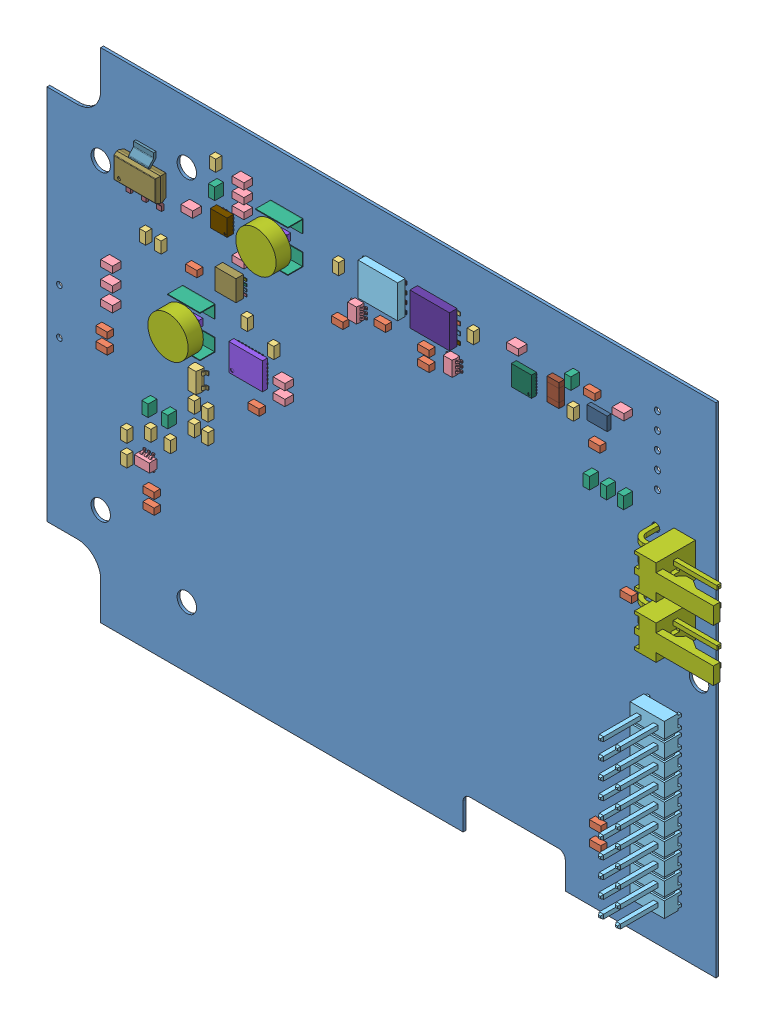
SolidWorks assembly PowerBoard, configuration Domyślna. Lengths in mm.
Overall size (104.97 74.1 12.18).
255 component instances, 64 part files, 0 mates.
Components (placement in the parent):
- PowerBoard.step-1: PowerBoard.step [Domyślna] at origin size (104.97 74.1 12.18)
  - Board.step-1: Board.step [Domyślna] at origin size (99.5 74.1 0.41)
    - Open CASCADE STEP translator 6.8 2.1.1.step-1: Open CASCADE STEP translator 6.8 2.1.1.step [Domyślna] at (0 0 -0.4115) size (99.5 74.1 0.41)
  - R13.step-1: R13.step [Domyślna] at origin size (1.7 0.95 0.9)
    - 6265950816.step-1: 6265950816.step [Domyślna] at (107.823 36.83 0) size (1.7 0.95 0.9)
      - Extruded.step-1: Extruded.step [Domyślna] at origin size (1.7 0.95 0.9)
  - R12.step-1: R12.step [Domyślna] at origin size (1.7 0.95 0.9)
    - 6265950816.step-1: 6265950816.step [Domyślna] at (107.823 34.29 0) size (1.7 0.95 0.9)
      - Extruded.step-1: Extruded.step [Domyślna] at origin size (1.7 0.95 0.9)
  - R41.step-1: R41.step [Domyślna] at origin size (0.95 1.7 0.9)
    - 6265951296.step-1: 6265951296.step [Domyślna] at (44.196 54.102 0) size (0.95 1.7 0.9)
      - Extruded-0.step-1: Extruded-0.step [Domyślna] at origin size (0.95 1.7 0.9)
  - T1.step-1: T1.step [Domyślna] at origin size (2.2 2.4 1.1)
    - SOT65P210X110-6N.step-1: SOT65P210X110-6N.step [Domyślna] at (40.6399 50.0381 0) x (0 1 0) z (0 0 1) size (2.4 2.2 1.1)
  - R22.step-1: R22.step [Domyślna] at origin size (0.95 1.7 0.9)
    - 6265951296.step-1: 6265951296.step [Domyślna] at (41.275 54.102 0) size (0.95 1.7 0.9)
      - Extruded-0.step-1: Extruded-0.step [Domyślna] at origin size (0.95 1.7 0.9)
  - R21.step-1: R21.step [Domyślna] at origin size (0.95 1.7 0.9)
    - 6265951296.step-1: 6265951296.step [Domyślna] at (37.719 49.022 0) size (0.95 1.7 0.9)
      - Extruded-0.step-1: Extruded-0.step [Domyślna] at origin size (0.95 1.7 0.9)
  - R20.step-1: R20.step [Domyślna] at origin size (1.7 0.95 0.9)
    - 6265950816.step-1: 6265950816.step [Domyślna] at (41.402 44.577 0) size (1.7 0.95 0.9)
      - Extruded.step-1: Extruded.step [Domyślna] at origin size (1.7 0.95 0.9)
  - R19.step-1: R19.step [Domyślna] at origin size (1.7 0.95 0.9)
    - 6265950816.step-1: 6265950816.step [Domyślna] at (41.402 46.609 0) size (1.7 0.95 0.9)
      - Extruded.step-1: Extruded.step [Domyślna] at origin size (1.7 0.95 0.9)
  - R18.step-1: R18.step [Domyślna] at origin size (0.95 1.7 0.9)
    - 6265951296.step-1: 6265951296.step [Domyślna] at (37.719 52.197 0) size (0.95 1.7 0.9)
      - Extruded-0.step-1: Extruded-0.step [Domyślna] at origin size (0.95 1.7 0.9)
  - R11.step-1: R11.step [Domyślna] at origin size (1.7 0.95 0.9)
    - 6265950816.step-1: 6265950816.step [Domyślna] at (112.395 68.707 0) size (1.7 0.95 0.9)
      - Extruded.step-1: Extruded.step [Domyślna] at origin size (1.7 0.95 0.9)
  - P1.step-1: P1.step [Domyślna] at origin size (5.08 25.4 11.3)
    - SAMTEC_TSW-110-23-L-D.step-1: SAMTEC_TSW-110-23-L-D.step [Domyślna] at (117.2211 44.4499 0) x (0 -1 0) z (0 0 1) size (25.4 5.08 11.3)
  - C16.step-1: C16.step [Domyślna] at origin size (0.95 1.75 1.3)
    - 6265949696.step-1: 6265949696.step [Domyślna] at (44.196 57.531 0) size (0.95 1.75 1.3)
      - Extruded-1.step-1: Extruded-1.step [Domyślna] at origin size (0.95 1.75 1.3)
  - C15.step-1: C15.step [Domyślna] at origin size (0.95 1.75 1.3)
    - 6265949696.step-1: 6265949696.step [Domyślna] at (41.275 57.531 0) size (0.95 1.75 1.3)
      - Extruded-1.step-1: Extruded-1.step [Domyślna] at origin size (0.95 1.75 1.3)
  - RTC.step-1: RTC.step [Domyślna] at origin size (14.74 5.08 9.64)
    - MOLEX_22-05-7028.step-1: MOLEX_22-05-7028.step [Domyślna] at (115.9486 69.977 0) x (0 -1 0) z (0 0 1) size (5.08 14.74 9.64)
  - EXT.step-1: EXT.step [Domyślna] at origin size (14.74 5.08 9.64)
    - MOLEX_22-05-7028.step-1: MOLEX_22-05-7028.step [Domyślna] at (115.9511 77.724 0) x (0 -1 0) z (0 0 1) size (5.08 14.74 9.64)
  - C3.step-1: C3.step [Domyślna] at origin size (0.95 1.75 1.3)
    - 6265949696.step-1: 6265949696.step [Domyślna] at (112.014 81.026 0) size (0.95 1.75 1.3)
      - Extruded-1.step-1: Extruded-1.step [Domyślna] at origin size (0.95 1.75 1.3)
  - C2.step-1: C2.step [Domyślna] at origin size (0.95 1.75 1.3)
    - 6265949696.step-1: 6265949696.step [Domyślna] at (109.474 81.026 0) size (0.95 1.75 1.3)
      - Extruded-1.step-1: Extruded-1.step [Domyślna] at origin size (0.95 1.75 1.3)
  - C1.step-1: C1.step [Domyślna] at origin size (0.95 1.75 1.3)
    - 6265949696.step-1: 6265949696.step [Domyślna] at (106.934 81.026 0) size (0.95 1.75 1.3)
      - Extruded-1.step-1: Extruded-1.step [Domyślna] at origin size (0.95 1.75 1.3)
  - IC3.step-1: IC3.step [Domyślna] at origin size (1.45 1.1 0.6)
    - 5965230816.step-1: 5965230816.step [Domyślna] at (34.417 59.055 -0.4115) x (0 -1 0) z (0 0 -1) size (1.1 1.45 0.6)
      - Body.step-1: Body.step [Domyślna] at origin size (1 1.45 0.55)
      - PinsArrayLR.step-1: PinsArrayLR.step [Domyślna] at origin size (1.1 1.2 0.07)
  - U1.step-1: U1.step [Domyślna] at origin size (3 2 0.6)
    - 6265946736.step-1: 6265946736.step [Domyślna] at (107.823 89.281 0) size (3 2 0.6)
      - Extruded-2.step-1: Extruded-2.step [Domyślna] at origin size (3 2 0.6)
  - R34.step-1: R34.step [Domyślna] at origin size (0.95 1.7 0.9)
    - 6265951296.step-1: 6265951296.step [Domyślna] at (59.563 73.914 0) size (0.95 1.7 0.9)
      - Extruded-0.step-1: Extruded-0.step [Domyślna] at origin size (0.95 1.7 0.9)
  - R33.step-1: R33.step [Domyślna] at origin size (0.95 1.7 0.9)
    - 6265951296.step-1: 6265951296.step [Domyślna] at (42.799 79.121 0) size (0.95 1.7 0.9)
      - Extruded-0.step-1: Extruded-0.step [Domyślna] at origin size (0.95 1.7 0.9)
  - R32.step-1: R32.step [Domyślna] at origin size (1.7 0.95 0.9)
    - 6265950816.step-1: 6265950816.step [Domyślna] at (75.819 85.344 0) size (1.7 0.95 0.9)
      - Extruded.step-1: Extruded.step [Domyślna] at origin size (1.7 0.95 0.9)
  - R31.step-1: R31.step [Domyślna] at origin size (0.95 1.7 0.9)
    - 6265951296.step-1: 6265951296.step [Domyślna] at (40.513 79.121 0) size (0.95 1.7 0.9)
      - Extruded-0.step-1: Extruded-0.step [Domyślna] at origin size (0.95 1.7 0.9)
  - R30.step-1: R30.step [Domyślna] at origin size (0.95 1.7 0.9)
    - 6265951296.step-1: 6265951296.step [Domyślna] at (69.215 89.535 0) size (0.95 1.7 0.9)
      - Extruded-0.step-1: Extruded-0.step [Domyślna] at origin size (0.95 1.7 0.9)
  - R29.step-1: R29.step [Domyślna] at origin size (1.7 0.95 0.9)
    - 6265950816.step-1: 6265950816.step [Domyślna] at (47.752 78.359 0) size (1.7 0.95 0.9)
      - Extruded.step-1: Extruded.step [Domyślna] at origin size (1.7 0.95 0.9)
  - R28.step-1: R28.step [Domyślna] at origin size (1.7 0.95 0.9)
    - 6265950816.step-1: 6265950816.step [Domyślna] at (107.696 85.725 0) size (1.7 0.95 0.9)
      - Extruded.step-1: Extruded.step [Domyślna] at origin size (1.7 0.95 0.9)
  - R27.step-1: R27.step [Domyślna] at origin size (1.75 3.35 0.8)
    - RESC3216X80N.step-1: RESC3216X80N.step [Domyślna] at (101.4729 89.5351 0) x (0 1 0) z (0 0 1) size (3.35 1.75 0.8)
  - R26.step-1: R26.step [Domyślna] at origin size (1.7 0.95 0.9)
    - 6265950816.step-1: 6265950816.step [Domyślna] at (69.469 82.55 0) size (1.7 0.95 0.9)
      - Extruded.step-1: Extruded.step [Domyślna] at origin size (1.7 0.95 0.9)
  - R25.step-1: R25.step [Domyślna] at origin size (1.7 0.95 0.9)
    - 6265950816.step-1: 6265950816.step [Domyślna] at (82.296 83.4136 0) size (1.7 0.95 0.9)
      - Extruded.step-1: Extruded.step [Domyślna] at origin size (1.7 0.95 0.9)
  - R24.step-1: R24.step [Domyślna] at origin size (0.95 1.7 0.9)
    - 6265951296.step-1: 6265951296.step [Domyślna] at (104.14 88.265 0) size (0.95 1.7 0.9)
      - Extruded-0.step-1: Extruded-0.step [Domyślna] at origin size (0.95 1.7 0.9)
  - R23.step-1: R23.step [Domyślna] at origin size (1.7 0.95 0.9)
    - 6265950816.step-1: 6265950816.step [Domyślna] at (106.934 92.075 0) size (1.7 0.95 0.9)
      - Extruded.step-1: Extruded.step [Domyślna] at origin size (1.7 0.95 0.9)
  - R17.step-1: R17.step [Domyślna] at origin size (0.95 1.7 0.9)
    - 6265951296.step-1: 6265951296.step [Domyślna] at (50.927 93.726 0) size (0.95 1.7 0.9)
      - Extruded-0.step-1: Extruded-0.step [Domyślna] at origin size (0.95 1.7 0.9)
  - R16.step-1: R16.step [Domyślna] at origin size (1.7 0.95 0.9)
    - 6265950816.step-1: 6265950816.step [Domyślna] at (34.417 61.722 0) size (1.7 0.95 0.9)
      - Extruded.step-1: Extruded.step [Domyślna] at origin size (1.7 0.95 0.9)
  - R15.step-1: R15.step [Domyślna] at origin size (1.7 0.95 0.9)
    - 6265950816.step-1: 6265950816.step [Domyślna] at (34.417 63.754 0) size (1.7 0.95 0.9)
      - Extruded.step-1: Extruded.step [Domyślna] at origin size (1.7 0.95 0.9)
  - R14.step-1: R14.step [Domyślna] at origin size (0.95 1.7 0.9)
    - 6265951296.step-1: 6265951296.step [Domyślna] at (49.784 60.96 0) size (0.95 1.7 0.9)
      - Extruded-0.step-1: Extruded-0.step [Domyślna] at origin size (0.95 1.7 0.9)
  - R_.step-1: R_.step [Domyślna] at origin size (0.95 1.7 0.9)
    - 6265951296.step-1: 6265951296.step [Domyślna] at (49.784 57.912 0) size (0.95 1.7 0.9)
      - Extruded-0.step-1: Extruded-0.step [Domyślna] at origin size (0.95 1.7 0.9)
  - R_-1.step-1: R_-1.step [Domyślna] at origin size (0.95 1.7 0.9)
    - 6265951296.step-1: 6265951296.step [Domyślna] at (47.752 60.96 0) size (0.95 1.7 0.9)
      - Extruded-0.step-1: Extruded-0.step [Domyślna] at origin size (0.95 1.7 0.9)
  - R40.step-1: R40.step [Domyślna] at origin size (0.95 1.7 0.9)
    - 6265951296.step-1: 6265951296.step [Domyślna] at (47.752 57.912 0) size (0.95 1.7 0.9)
      - Extruded-0.step-1: Extruded-0.step [Domyślna] at origin size (0.95 1.7 0.9)
  - Q2.step-1: Q2.step [Domyślna] at origin size (3.78 3.1 1.22)
    - 5965226256.step-1: 5965226256.step [Domyślna] at (53.182 79.451 0) x (-1 0 0) z (0 0 1) size (3.78 3.1 1.22)
      - Body-3.step-1: Body-3.step [Domyślna] at (0 0 0.1) size (3.1 3.1 1.12)
      - ('pin.step-1: ('pin.step [Domyślna] at (-2.0095 0.828 0) size (0.91 0.32 0.1)
      - ('pin-4.step-1: ('pin-4.step [Domyślna] at (-2.0095 0.168 0) size (0.91 0.32 0.1)
      - ('pin-5.step-1: ('pin-5.step [Domyślna] at (-2.0095 -0.492 0) size (0.91 0.32 0.1)
      - ('pin-6.step-1: ('pin-6.step [Domyślna] at (-2.0095 -1.152 0) size (0.91 0.32 0.1)
      - ('pin-7.step-1: ('pin-7.step [Domyślna] at (1.3405 -1.152 0) size (0.43 0.32 0.1)
      - ('pin-8.step-1: ('pin-8.step [Domyślna] at (1.3405 -0.492 0) size (0.43 0.32 0.1)
      - ('pin-9.step-1: ('pin-9.step [Domyślna] at (1.3405 0.168 0) size (0.43 0.32 0.1)
      - ('pin-10.step-1: ('pin-10.step [Domyślna] at (1.3405 0.828 0) size (0.43 0.32 0.1)
      - ('pin-11.step-1: ('pin-11.step [Domyślna] at (-0.252 -0.945 0) size (1.38 1.89 0.1)
      - ('pin-12.step-1: ('pin-12.step [Domyślna] at (1.0575 1.125 0) size (0.23 0.06 0.1)
      - ('pin-13.step-1: ('pin-13.step [Domyślna] at (1.0575 -1.185 0) size (0.23 0.06 0.1)
  - L2.step-1: L2.step [Domyślna] at origin size (6 6.2 4.6)
    - 5965222976.step-1: 5965222976.step [Domyślna] at (48.006 71.882 0) x (0 1 0) z (0 0 1) size (6.2 6 4.6)
      - pin.step-1: pin.step [Domyślna] at (3.1 2.4 0) x (-1 0 0) z (0 0 1) size (1.9 4.8 2.25)
        - Open_CASCADE_STEP_translator_6.8_1.3.1.step-1: Open_CASCADE_STEP_translator_6.8_1.3.1.step [Domyślna] at origin size (1.9 4.8 2.25)
      - pin.step-2: pin.step [Domyślna] at (-3.1 -2.4 0) size (1.9 4.8 2.25)
        - Open_CASCADE_STEP_translator_6.8_1.3.1.step-1: Open_CASCADE_STEP_translator_6.8_1.3.1.step [Domyślna] at origin size (1.9 4.8 2.25)
      - Body.step-1: Body.step [Domyślna] at (0 0 0.1) size (1 1.45 0.55)
      - cylinder.step-1: cylinder.step [Domyślna] at (0 0 0.1) size (6 6 2.25)
  - L1.step-1: L1.step [Domyślna] at origin size (6 6.2 4.6)
    - 5965222976.step-1: 5965222976.step [Domyślna] at (61.087 89.408 0) x (0 1 0) z (0 0 1) size (6.2 6 4.6)
      - pin.step-1: pin.step [Domyślna] at (3.1 2.4 0) x (-1 0 0) z (0 0 1) size (1.9 4.8 2.25)
        - Open_CASCADE_STEP_translator_6.8_1.3.1.step-1: Open_CASCADE_STEP_translator_6.8_1.3.1.step [Domyślna] at origin size (1.9 4.8 2.25)
      - pin.step-2: pin.step [Domyślna] at (-3.1 -2.4 0) size (1.9 4.8 2.25)
        - Open_CASCADE_STEP_translator_6.8_1.3.1.step-1: Open_CASCADE_STEP_translator_6.8_1.3.1.step [Domyślna] at origin size (1.9 4.8 2.25)
      - Body.step-1: Body.step [Domyślna] at (0 0 0.1) size (1 1.45 0.55)
      - cylinder.step-1: cylinder.step [Domyślna] at (0 0 0.1) size (6 6 2.25)
  - IC6.step-1: IC6.step [Domyślna] at origin size (5.1 4.1 0.8)
    - 5965220016.step-1: 5965220016.step [Domyślna] at (55.753 69.977 0) x (0 1 0) z (0 0 1) size (4.1 5.1 0.8)
      - Body-14.step-1: Body-14.step [Domyślna] at origin size (4 5 0.75)
      - ThermalPin.step-1: ThermalPin.step [Domyślna] at (-1.325 -1.825 0) size (2.65 3.65 0.1)
      - PinsArrayLR-15.step-1: PinsArrayLR-15.step [Domyślna] at origin size (4.1 3.75 0.1)
      - PinsArrayTB.step-1: PinsArrayTB.step [Domyślna] at origin size (2.75 5.1 0.1)
  - IC5.step-1: IC5.step [Domyślna] at origin size (6.5 7 1.7)
    - 5965221536.step-1: 5965221536.step [Domyślna] at (40.132 86.741 0) x (0 1 0) z (0 0 1) size (7 6.5 1.7)
      - Body-16.step-1: Body-16.step [Domyślna] at origin size (3.5 6.5 1.62)
      - PinsArrayL.step-1: PinsArrayL.step [Domyślna] at origin size (1.75 5.3 1.11)
      - FilletPinR.step-1: FilletPinR.step [Domyślna] at origin size (1.75 3 1.11)
  - IC4.step-1: IC4.step [Domyślna] at origin size (3.1 3 0.8)
    - 5965222496.step-1: 5965222496.step [Domyślna] at (96.774 88.646 0) x (-1 0 0) z (0 0 1) size (3.1 3 0.8)
      - Body-17.step-1: Body-17.step [Domyślna] at origin size (3 3 0.75)
      - ThermalPin-18.step-1: ThermalPin-18.step [Domyślna] at (-0.85 -1.15 0) size (1.7 2.3 0.1)
      - PinsArrayLR-19.step-1: PinsArrayLR-19.step [Domyślna] at origin size (3.1 2.6 0.1)
  - IC2.step-1: IC2.step [Domyślna] at origin size (2.6 2.6 1)
    - 5965226416.step-1: 5965226416.step [Domyślna] at (51.943 86.6902 0) x (-1 0 0) z (0 0 1) size (2.6 2.6 1)
      - Body-20.step-1: Body-20.step [Domyślna] at origin size (2.5 2.5 0.95)
      - PinsArrayLR-21.step-1: PinsArrayLR-21.step [Domyślna] at origin size (2.6 1.75 0.1)
      - PinsArrayTB-22.step-1: PinsArrayTB-22.step [Domyślna] at origin size (0.75 2.6 0.1)
  - D1.step-1: D1.step [Domyślna] at origin size (2.5 3 1.3)
    - SOT95P240X130-3N.step-1: SOT95P240X130-3N.step [Domyślna] at (48.2599 64.6429 0) x (-1 0 0) z (0 0 1) size (2.5 3 1.3)
  - C19.step-1: C19.step [Domyślna] at origin size (1.75 0.95 1.3)
    - 6265696752.step-1: 6265696752.step [Domyślna] at (61.214 68.707 0) size (1.75 0.95 1.3)
      - Extruded-23.step-1: Extruded-23.step [Domyślna] at origin size (1.75 0.95 1.3)
  - C18.step-1: C18.step [Domyślna] at origin size (1.75 0.95 1.3)
    - 6265696752.step-1: 6265696752.step [Domyślna] at (61.214 70.739 0) size (1.75 0.95 1.3)
      - Extruded-23.step-1: Extruded-23.step [Domyślna] at origin size (1.75 0.95 1.3)
  - C17.step-1: C17.step [Domyślna] at origin size (1.75 0.95 1.3)
    - 6265696752.step-1: 6265696752.step [Domyślna] at (47.498 86.106 0) size (1.75 0.95 1.3)
      - Extruded-23.step-1: Extruded-23.step [Domyślna] at origin size (1.75 0.95 1.3)
  - C14.step-1: C14.step [Domyślna] at origin size (1.75 0.95 1.3)
    - 6265696752.step-1: 6265696752.step [Domyślna] at (95.9358 92.5576 0) size (1.75 0.95 1.3)
      - Extruded-23.step-1: Extruded-23.step [Domyślna] at origin size (1.75 0.95 1.3)
  - C13.step-1: C13.step [Domyślna] at origin size (1.75 0.95 1.3)
    - 6265696752.step-1: 6265696752.step [Domyślna] at (111.633 92.075 0) size (1.75 0.95 1.3)
      - Extruded-23.step-1: Extruded-23.step [Domyślna] at origin size (1.75 0.95 1.3)
  - C12.step-1: C12.step [Domyślna] at origin size (0.95 1.75 1.3)
    - 6265949696.step-1: 6265949696.step [Domyślna] at (104.14 92.456 0) size (0.95 1.75 1.3)
      - Extruded-1.step-1: Extruded-1.step [Domyślna] at origin size (0.95 1.75 1.3)
  - C11.step-1: C11.step [Domyślna] at origin size (0.95 1.75 1.3)
    - 6265949696.step-1: 6265949696.step [Domyślna] at (51.181 90.424 0) size (0.95 1.75 1.3)
      - Extruded-1.step-1: Extruded-1.step [Domyślna] at origin size (0.95 1.75 1.3)
  - C10.step-1: C10.step [Domyślna] at origin size (1.75 0.95 1.3)
    - 6265696752.step-1: 6265696752.step [Domyślna] at (55.118 93.5482 0) size (1.75 0.95 1.3)
      - Extruded-23.step-1: Extruded-23.step [Domyślna] at origin size (1.75 0.95 1.3)
  - C9.step-1: C9.step [Domyślna] at origin size (1.75 0.95 1.3)
    - 6265696752.step-1: 6265696752.step [Domyślna] at (55.118 91.6432 0) size (1.75 0.95 1.3)
      - Extruded-23.step-1: Extruded-23.step [Domyślna] at origin size (1.75 0.95 1.3)
  - C8.step-1: C8.step [Domyślna] at origin size (1.75 0.95 1.3)
    - 6265696752.step-1: 6265696752.step [Domyślna] at (55.118 83.3882 0) size (1.75 0.95 1.3)
      - Extruded-23.step-1: Extruded-23.step [Domyślna] at origin size (1.75 0.95 1.3)
  - C7.step-1: C7.step [Domyślna] at origin size (1.75 0.95 1.3)
    - 6265696752.step-1: 6265696752.step [Domyślna] at (55.118 89.7382 0) size (1.75 0.95 1.3)
      - Extruded-23.step-1: Extruded-23.step [Domyślna] at origin size (1.75 0.95 1.3)
  - C6.step-1: C6.step [Domyślna] at origin size (1.75 0.95 1.3)
    - 6265696752.step-1: 6265696752.step [Domyślna] at (35.56 67.945 0) size (1.75 0.95 1.3)
      - Extruded-23.step-1: Extruded-23.step [Domyślna] at origin size (1.75 0.95 1.3)
  - C5.step-1: C5.step [Domyślna] at origin size (1.75 0.95 1.3)
    - 6265696752.step-1: 6265696752.step [Domyślna] at (35.56 73.025 0) size (1.75 0.95 1.3)
      - Extruded-23.step-1: Extruded-23.step [Domyślna] at origin size (1.75 0.95 1.3)
  - C4.step-1: C4.step [Domyślna] at origin size (1.75 0.95 1.3)
    - 6265696752.step-1: 6265696752.step [Domyślna] at (35.56 70.485 0) size (1.75 0.95 1.3)
      - Extruded-23.step-1: Extruded-23.step [Domyślna] at origin size (1.75 0.95 1.3)
  - R35.step-1: R35.step [Domyślna] at origin size (0.95 1.7 0.9)
    - 6265951296.step-1: 6265951296.step [Domyślna] at (89.281 90.678 0) size (0.95 1.7 0.9)
      - Extruded-0.step-1: Extruded-0.step [Domyślna] at origin size (0.95 1.7 0.9)
  - R36.step-1: R36.step [Domyślna] at origin size (1.7 0.95 0.9)
    - 6265950816.step-1: 6265950816.step [Domyślna] at (82.296 85.344 0) size (1.7 0.95 0.9)
      - Extruded.step-1: Extruded.step [Domyślna] at origin size (1.7 0.95 0.9)
  - R37.step-1: R37.step [Domyślna] at origin size (1.7 0.95 0.9)
    - 6265950816.step-1: 6265950816.step [Domyślna] at (57.023 65.151 0) size (1.7 0.95 0.9)
      - Extruded.step-1: Extruded.step [Domyślna] at origin size (1.7 0.95 0.9)
  - R38.step-1: R38.step [Domyślna] at origin size (0.95 1.7 0.9)
    - 6265951296.step-1: 6265951296.step [Domyślna] at (55.626 75.565 0) size (0.95 1.7 0.9)
      - Extruded-0.step-1: Extruded-0.step [Domyślna] at origin size (0.95 1.7 0.9)
  - Q1.step-1: Q1.step [Domyślna] at origin size (6.49 4.9 1.22)
    - 5965226896.step-1: 5965226896.step [Domyślna] at (75.835 90.043 0) x (1 0 0) z (0 0 1) size (6.49 4.9 1.22)
      - Body-24.step-1: Body-24.step [Domyślna] at (0 0 0.1) size (5.89 4.9 1.12)
      - ('pin-25.step-1: ('pin-25.step [Domyślna] at (-3.384 1.661 0) size (1.15 0.49 0.1)
      - ('pin-26.step-1: ('pin-26.step [Domyślna] at (-3.384 0.391 0) size (1.15 0.49 0.1)
      - ('pin-27.step-1: ('pin-27.step [Domyślna] at (-3.384 -0.879 0) size (1.15 0.49 0.1)
      - ('pin-28.step-1: ('pin-28.step [Domyślna] at (-3.384 -2.149 0) size (1.15 0.49 0.1)
      - ('pin-29.step-1: ('pin-29.step [Domyślna] at (2.516 -2.149 0) size (0.59 0.49 0.1)
      - ('pin-30.step-1: ('pin-30.step [Domyślna] at (2.516 -0.879 0) size (0.59 0.49 0.1)
      - ('pin-31.step-1: ('pin-31.step [Domyślna] at (2.516 0.391 0) size (0.59 0.49 0.1)
      - ('pin-32.step-1: ('pin-32.step [Domyślna] at (2.516 1.661 0) size (0.59 0.49 0.1)
      - ('pin-33.step-1: ('pin-33.step [Domyślna] at (-0.974 -1.574 0) size (3.05 3.15 0.1)
      - ('pin-34.step-1: ('pin-34.step [Domyślna] at (2.1705 1.981 0) size (0.26 0.2 0.1)
      - ('pin-35.step-1: ('pin-35.step [Domyślna] at (2.1705 -2.185 0) size (0.26 0.2 0.1)
  - Q3.step-1: Q3.step [Domyślna] at origin size (6.49 4.9 1.22)
    - 5965226976.step-1: 5965226976.step [Domyślna] at (83.55 90.043 0) x (-1 0 0) z (0 0 1) size (6.49 4.9 1.22)
      - Body-36.step-1: Body-36.step [Domyślna] at (0 0 0.1) size (5.89 4.9 1.12)
      - ('pin-37.step-1: ('pin-37.step [Domyślna] at (-3.384 1.661 0) size (1.15 0.49 0.1)
      - ('pin-38.step-1: ('pin-38.step [Domyślna] at (-3.384 0.391 0) size (1.15 0.49 0.1)
      - ('pin-39.step-1: ('pin-39.step [Domyślna] at (-3.384 -0.879 0) size (1.15 0.49 0.1)
      - ('pin-40.step-1: ('pin-40.step [Domyślna] at (-3.384 -2.149 0) size (1.15 0.49 0.1)
      - ('pin-41.step-1: ('pin-41.step [Domyślna] at (2.516 -2.149 0) size (0.59 0.49 0.1)
      - ('pin-42.step-1: ('pin-42.step [Domyślna] at (2.516 -0.879 0) size (0.59 0.49 0.1)
      - ('pin-43.step-1: ('pin-43.step [Domyślna] at (2.516 0.391 0) size (0.59 0.49 0.1)
      - ('pin-44.step-1: ('pin-44.step [Domyślna] at (2.516 1.661 0) size (0.59 0.49 0.1)
      - ('pin-45.step-1: ('pin-45.step [Domyślna] at (-0.974 -1.574 0) size (3.05 3.15 0.1)
      - ('pin-46.step-1: ('pin-46.step [Domyślna] at (2.1705 1.981 0) size (0.26 0.2 0.1)
      - ('pin-47.step-1: ('pin-47.step [Domyślna] at (2.1705 -2.185 0) size (0.26 0.2 0.1)
  - T2.step-1: T2.step [Domyślna] at origin size (2.4 2.2 1.1)
    - SOT65P210X110-6N.step-1: SOT65P210X110-6N.step [Domyślna] at (71.8819 85.0899 0) x (-1 0 0) z (0 0 1) size (2.4 2.2 1.1)
  - T3.step-1: T3.step [Domyślna] at origin size (2.4 2.2 1.1)
    - SOT65P210X110-6N.step-1: SOT65P210X110-6N.step [Domyślna] at (86.1061 85.3441 0) x (1 0 0) z (0 0 1) size (2.4 2.2 1.1)
